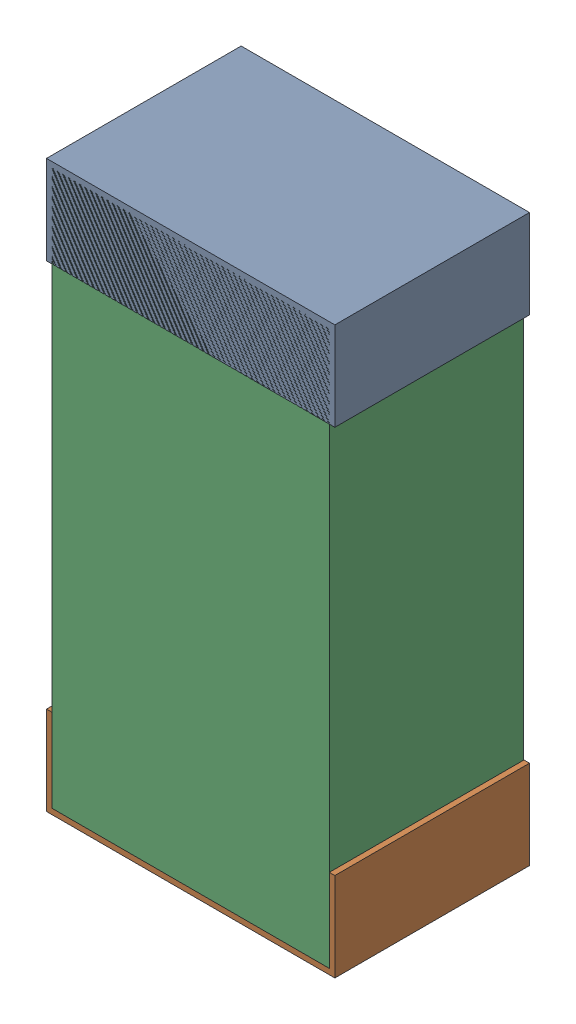
SolidWorks assembly C32, configuration Default. Lengths in mm.
Overall size (0.52 1.02 0.35).
6 component instances, 2 part files, 0 mates.
Components (placement in the parent):
- 870941120-1: 870941120 [Default] at (22.148 19.554 -1.9516) size (0.52 0.16 0.35)
  - Extruded_3-1: Extruded_3 [Default] at origin size (0.52 0.16 0.35)
- 870941120-2: 870941120 [Default] at (22.148 18.694 -1.9516) size (0.52 0.16 0.35)
  - Extruded_3-1: Extruded_3 [Default] at origin size (0.52 0.16 0.35)
- 870941280-1: 870941280 [Default] at (22.148 19.124 -1.9506) size (0.5 1 0.35)
  - Extruded_4-1: Extruded_4 [Default] at origin size (0.5 1 0.35)
